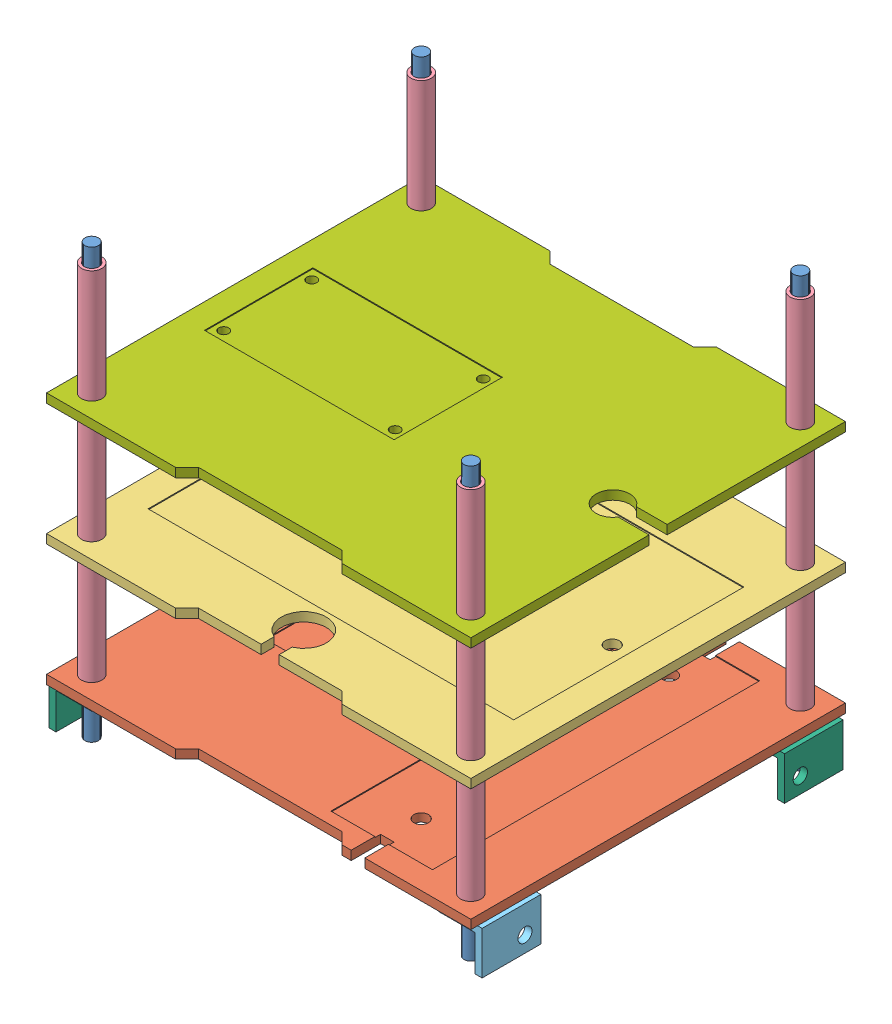
SolidWorks assembly PCB_Stack_3, configuration Default. Lengths in mm.
Overall size (96 95 83).
23 component instances, 7 part files, 68 mates.
Components (placement in the parent):
- PCB_Rod_2-1: PCB_Rod_2 [Default] at origin size (3 95 3)
- PCB_Rod_2-2: PCB_Rod_2 [Default] at (-84 0 0.0003) x (-0.139284 0 0.990253) z (-0.990253 0 -0.139284) size (3 95 3)
- PCB_Rod_2-3: PCB_Rod_2 [Default] at (-83.9998 0 73.0003) x (0.037489 0 0.999297) z (-0.999297 0 0.037489) size (3 95 3)
- PCB_Rod_2-4: PCB_Rod_2 [Default] at (0.0002 0 73) x (0.981991 0 -0.188925) z (0.188925 0 0.981991) size (3 95 3)
- PCB_Battery-1: PCB_Battery [Default] at (-41.9999 10 36.5001) x (-1 0 0.000003) z (-0.000003 0 -1) size (94 2 83)
- PCB-2: PCB [Default] at (-41.9999 37 36.5001) x (1 0 -0.000003) z (0.000003 0 1) size (94 2 83)
- Aluminum Unthreaded Spacer_Battery-1: Aluminum Unthreaded Spacer_Battery [94669A105] at (0 24.5 0) x (0.317635 0 -0.948213) z (0 1 0) size (4.5 4.5 25)
- Aluminum Unthreaded Spacer_Battery-2: Aluminum Unthreaded Spacer_Battery [94669A105] at (0 51.5 0) x (0.317635 0 -0.948213) z (0 1 0) size (4.5 4.5 25)
- Aluminum Unthreaded Spacer_Battery-3: Aluminum Unthreaded Spacer_Battery [94669A105] at (0 78.5 0) x (-0.841831 0 -0.539741) z (0 1 0) size (4.5 4.5 25)
- Aluminum Unthreaded Spacer_Battery-4: Aluminum Unthreaded Spacer_Battery [94669A105] at (0.0002 24.5 73) x (0.317635 0 -0.948213) z (0 1 0) size (4.5 4.5 25)
- Aluminum Unthreaded Spacer_Battery-5: Aluminum Unthreaded Spacer_Battery [94669A105] at (0.0002 51.5 73) x (0.317635 0 -0.948213) z (0 1 0) size (4.5 4.5 25)
- Aluminum Unthreaded Spacer_Battery-6: Aluminum Unthreaded Spacer_Battery [94669A105] at (0.0002 78.5 73) x (-0.286549 0 -0.958066) z (0 1 0) size (4.5 4.5 25)
- Aluminum Unthreaded Spacer_Battery-7: Aluminum Unthreaded Spacer_Battery [94669A105] at (-83.9998 24.5 73.0003) x (0.317635 0 -0.948213) z (0 1 0) size (4.5 4.5 25)
- Aluminum Unthreaded Spacer_Battery-8: Aluminum Unthreaded Spacer_Battery [94669A105] at (-83.9998 51.5 73.0003) x (0.317635 0 -0.948213) z (0 1 0) size (4.5 4.5 25)
- Aluminum Unthreaded Spacer_Battery-9: Aluminum Unthreaded Spacer_Battery [94669A105] at (-83.9998 78.5 73.0003) x (-0.883236 0 -0.468929) z (0 1 0) size (4.5 4.5 25)
- Aluminum Unthreaded Spacer_Battery-10: Aluminum Unthreaded Spacer_Battery [94669A105] at (-84 51.5 0.0003) x (0.317635 0 -0.948213) z (0 1 0) size (4.5 4.5 25)
- Aluminum Unthreaded Spacer_Battery-11: Aluminum Unthreaded Spacer_Battery [94669A105] at (-84 78.5 0.0003) x (-0.872408 0 -0.488777) z (0 1 0) size (4.5 4.5 25)
- Aluminum Unthreaded Spacer_Battery-12: Aluminum Unthreaded Spacer_Battery [94669A105] at (-84 24.5 0.0003) x (0.317635 0 -0.948213) z (0 1 0) size (4.5 4.5 25)
- 88805K144_Architectural 6063 Aluminum 90 Degree Angle-1: 88805K144_Architectural 6063 Aluminum 90 Degree Angle [88805K144] at (-85.2375 5.2375 3.0003) x (-1 0 0.000003) z (0.000003 0 1) size (9.53 9.53 13)
- 88805K144_Architectural 6063 Aluminum 90 Degree Angle-2: 88805K144_Architectural 6063 Aluminum 90 Degree Angle [88805K144] at (1.2377 5.2375 70) x (0 1 0) z (0.000003 0 1) size (9.53 9.53 13)
- PCB_Bracket_1_(88805K144_Architectural 6063 Aluminum 90 Degree Angle)-1: PCB_Bracket_1_(88805K144_Architectural 6063 Aluminum 90 Degree Angle) [88805K144] at (1.2375 5.2375 3) x (0 1 0) z (0.000003 0 1) size (9.53 9.53 13)
- PCB_Bracket_1_(88805K144_Architectural 6063 Aluminum 90 Degree Angle)-2: PCB_Bracket_1_(88805K144_Architectural 6063 Aluminum 90 Degree Angle) [88805K144] at (-85.2373 5.2375 70.0003) x (0 1 0) z (-0.000003 0 -1) size (9.53 9.53 13)
- PCB2-1: PCB2 [Default] at (-41.9999 64 36.5001) x (1 0 -0.000003) z (0.000003 0 1) size (94 2 83)
Mates (geometry in assembly coordinates):
- Concentric1: concentric aligned: cylinder of PCB_Rod_2-1 through (0 95 0) axis (0 -1 0) radius 1.5; cylinder of PCB_Battery-1 through (0 12 0) axis (0 -1 0) radius 1.5875
- Concentric2: concentric aligned: cylinder of PCB_Rod_2-4 through (0.0002 95 73) axis (0 -1 0) radius 1.5; cylinder of PCB_Battery-1 through (0.0002 12 73) axis (0 -1 0) radius 1.5875
- Concentric3: concentric aligned: cylinder of PCB_Rod_2-3 through (-83.9998 95 73.0003) axis (0 -1 0) radius 1.5; cylinder of PCB_Battery-1 through (-83.9998 12 73.0003) axis (0 -1 0) radius 1.5875
- Concentric4: concentric aligned: cylinder of PCB_Rod_2-2 through (-84 95 0.0003) axis (0 -1 0) radius 1.5; cylinder of PCB_Battery-1 through (-84 12 0.0003) axis (0 -1 0) radius 1.5875
- Concentric10: concentric aligned: cylinder of PCB_Rod_2-2 through (-84 95 0.0003) axis (0 -1 0) radius 1.5; cylinder of PCB-2 through (-84 39 0.0003) axis (0 -1 0) radius 1.5875
- Concentric11: concentric aligned: cylinder of PCB_Rod_2-3 through (-83.9998 95 73.0003) axis (0 -1 0) radius 1.5; cylinder of PCB-2 through (-83.9998 39 73.0003) axis (0 -1 0) radius 1.5875
- Concentric12: concentric aligned: cylinder of PCB_Rod_2-1 through (0 95 0) axis (0 -1 0) radius 1.5; cylinder of PCB-2 through (0 39 0) axis (0 -1 0) radius 1.5875
- Concentric13: concentric aligned: cylinder of PCB_Rod_2-4 through (0.0002 95 73) axis (0 -1 0) radius 1.5; cylinder of PCB-2 through (0.0002 39 73) axis (0 -1 0) radius 1.5875
- Distance1: distance = 25 mm anti-aligned: plane of PCB-2 through (-41.9999 37 36.5001) normal (0 -1 0); plane of PCB_Battery-1 through (-41.9999 12 36.5001) normal (0 1 0)
- Concentric14: concentric aligned: cylinder of PCB_Rod_2-4 through (0.0002 95 73) axis (0 -1 0) radius 1.5; cylinder of PCB-1 through (0.0002 66 73) axis (0 -1 0) radius 1.5
- Concentric15: concentric aligned: cylinder of PCB_Rod_2-1 through (0 95 0) axis (0 -1 0) radius 1.5; cylinder of PCB-1 through (0 66 0) axis (0 -1 0) radius 1.5
- Distance2: distance = 25 mm anti-aligned: plane of PCB-1 through (-41.9999 64 36.5001) normal (0 -1 0); plane of PCB-2 through (-41.9999 39 36.5001) normal (0 1 0)
- Concentric16: concentric anti-aligned: cylinder of PCB_Rod_2-1 through (0 95 0) axis (0 -1 0) radius 1.5; cylinder of Mounting_Standoff-1 through (0 4 0) axis (0 1 0) radius 1.55
- Coincident1: coincident anti-aligned: plane of Mounting_Standoff-1 through (-41.9999 10 36.5001) normal (0 1 0); plane of PCB_Battery-1 through (-41.9999 10 36.5001) normal (0 -1 0)
- Parallel1: parallel aligned: plane of Mounting_Standoff-1 through (6 4 -7.5) normal (1 0 -0.000003); plane of PCB_Battery-1 through (5 12 -5) normal (1 0 -0.000003)
- Concentric17: concentric aligned: cylinder of PCB_Rod_2-2 through (-84 95 0.0003) axis (0 -1 0) radius 1.5; cylinder of Mounting_Standoff-2 through (-84 10 0.0003) axis (0 -1 0) radius 1.55
- Parallel3: parallel aligned: plane of PCB_Battery-1 through (-89 12 -4.9997) normal (-1 0 0.000003); plane of Mounting_Standoff-2 through (-90 10 -7.4997) normal (-1 0 0.000003)
- Coincident2: coincident anti-aligned: plane of PCB_Battery-1 through (-41.9999 10 36.5001) normal (0 -1 0); plane of Mounting_Standoff-2 through (-41.9999 10 36.5001) normal (0 1 0)
- Concentric18: concentric aligned: cylinder of PCB_Rod_2-4 through (0.0002 95 73) axis (0 -1 0) radius 1.5; cylinder of Mounting_Standoff-3 through (0.0002 10 73) axis (0 -1 0) radius 1.55
- Coincident3: coincident anti-aligned: plane of PCB_Battery-1 through (-41.9999 10 36.5001) normal (0 -1 0); plane of Mounting_Standoff-3 through (-41.9999 10 36.5001) normal (0 1 0)
- Parallel4: parallel aligned: plane of PCB_Battery-1 through (5.0003 12 78) normal (0.000003 0 1); plane of Mounting_Standoff-3 through (0.5003 10 80.5) normal (0.000003 0 1)
- Concentric19: concentric anti-aligned: cylinder of PCB_Rod_2-3 through (-83.9998 95 73.0003) axis (0 -1 0) radius 1.5; cylinder of Mounting_Standoff-4 through (-83.9998 4 73.0003) axis (0 1 0) radius 1.55
- Coincident5: coincident anti-aligned: plane of PCB_Battery-1 through (-41.9999 10 36.5001) normal (0 -1 0); plane of Mounting_Standoff-4 through (-41.9999 10 36.5001) normal (0 1 0)
- Parallel5: parallel aligned: plane of PCB_Battery-1 through (5.0003 12 78) normal (0.000003 0 1); plane of Mounting_Standoff-4 through (-84.4997 4 80.5003) normal (0.000003 0 1)
- Distance3: distance = 10 mm aligned: plane of PCB_Battery-1 through (-41.9999 10 36.5001) normal (0 -1 0); plane of PCB_Rod_2-1 through (0 0 0) normal (0 -1 0)
- Coincident6: coincident aligned: plane of PCB_Rod_2-1 through (0 0 0) normal (0 -1 0); plane of PCB_Rod_2-4 through (0.0002 0 73) normal (0 -1 0)
- Coincident7: coincident aligned: plane of PCB_Rod_2-1 through (0 0 0) normal (0 -1 0); plane of PCB_Rod_2-2 through (-84 0 0.0003) normal (0 -1 0)
- Coincident8: coincident aligned: plane of PCB_Rod_2-1 through (0 0 0) normal (0 -1 0); plane of PCB_Rod_2-3 through (-83.9998 0 73.0003) normal (0 -1 0)
- Concentric20: concentric aligned: cylinder of PCB_Rod_2-1 through (0 95 0) axis (0 -1 0) radius 1.5; cylinder of Aluminum Unthreaded Spacer_Battery-1 through (0 37 0) axis (0 -1 0) radius 1.6
- Coincident9: coincident anti-aligned: plane of PCB-2 through (-41.9999 37 36.5001) normal (0 -1 0); plane of Aluminum Unthreaded Spacer_Battery-1 through (0 37 0) normal (0 1 0)
- Concentric21: concentric aligned: cylinder of PCB_Rod_2-1 through (0 95 0) axis (0 -1 0) radius 1.5; cylinder of Aluminum Unthreaded Spacer_Battery-2 through (0 64 0) axis (0 -1 0) radius 1.6
- Coincident10: coincident anti-aligned: plane of PCB-1 through (-41.9999 64 36.5001) normal (0 -1 0); plane of Aluminum Unthreaded Spacer_Battery-2 through (0 64 0) normal (0 1 0)
- Concentric22: concentric aligned: cylinder of PCB_Rod_2-1 through (0 95 0) axis (0 -1 0) radius 1.5; cylinder of Aluminum Unthreaded Spacer_Battery-3 through (0 91 0) axis (0 -1 0) radius 1.6
- Coincident11: coincident anti-aligned: plane of PCB-1 through (-41.9999 66 36.5001) normal (0 1 0); plane of Aluminum Unthreaded Spacer_Battery-3 through (0 66 0) normal (0 -1 0)
- Concentric23: concentric aligned: cylinder of PCB_Rod_2-4 through (0.0002 95 73) axis (0 -1 0) radius 1.5; cylinder of Aluminum Unthreaded Spacer_Battery-4 through (0.0002 37 73) axis (0 -1 0) radius 1.6
- Coincident12: coincident anti-aligned: plane of PCB-2 through (-41.9999 37 36.5001) normal (0 -1 0); plane of Aluminum Unthreaded Spacer_Battery-4 through (0.0002 37 73) normal (0 1 0)
- Concentric24: concentric aligned: cylinder of PCB_Rod_2-4 through (0.0002 95 73) axis (0 -1 0) radius 1.5; cylinder of Aluminum Unthreaded Spacer_Battery-5 through (0.0002 64 73) axis (0 -1 0) radius 1.6
- Coincident13: coincident anti-aligned: plane of PCB-1 through (-41.9999 64 36.5001) normal (0 -1 0); plane of Aluminum Unthreaded Spacer_Battery-5 through (0.0002 64 73) normal (0 1 0)
- Concentric25: concentric aligned: cylinder of PCB_Rod_2-4 through (0.0002 95 73) axis (0 -1 0) radius 1.5; cylinder of Aluminum Unthreaded Spacer_Battery-6 through (0.0002 91 73) axis (0 -1 0) radius 1.6
- Coincident14: coincident anti-aligned: plane of PCB-1 through (-41.9999 66 36.5001) normal (0 1 0); plane of Aluminum Unthreaded Spacer_Battery-6 through (0.0002 66 73) normal (0 -1 0)
- Concentric26: concentric aligned: cylinder of PCB_Rod_2-3 through (-83.9998 95 73.0003) axis (0 -1 0) radius 1.5; cylinder of Aluminum Unthreaded Spacer_Battery-7 through (-83.9998 37 73.0003) axis (0 -1 0) radius 1.6
- Coincident15: coincident anti-aligned: plane of PCB-2 through (-41.9999 37 36.5001) normal (0 -1 0); plane of Aluminum Unthreaded Spacer_Battery-7 through (-83.9998 37 73.0003) normal (0 1 0)
- Concentric27: concentric aligned: cylinder of PCB_Rod_2-3 through (-83.9998 95 73.0003) axis (0 -1 0) radius 1.5; cylinder of Aluminum Unthreaded Spacer_Battery-8 through (-83.9998 64 73.0003) axis (0 -1 0) radius 1.6
- Coincident16: coincident anti-aligned: plane of PCB-1 through (-41.9999 64 36.5001) normal (0 -1 0); plane of Aluminum Unthreaded Spacer_Battery-8 through (-83.9998 64 73.0003) normal (0 1 0)
- Concentric28: concentric aligned: cylinder of PCB_Rod_2-3 through (-83.9998 95 73.0003) axis (0 -1 0) radius 1.5; cylinder of Aluminum Unthreaded Spacer_Battery-9 through (-83.9998 91 73.0003) axis (0 -1 0) radius 1.6
- Coincident17: coincident anti-aligned: plane of PCB-1 through (-41.9999 66 36.5001) normal (0 1 0); plane of Aluminum Unthreaded Spacer_Battery-9 through (-83.9998 66 73.0003) normal (0 -1 0)
- Concentric29: concentric aligned: cylinder of PCB_Rod_2-2 through (-84 95 0.0003) axis (0 -1 0) radius 1.5; cylinder of Aluminum Unthreaded Spacer_Battery-12 through (-84 37 0.0003) axis (0 -1 0) radius 1.6
- Coincident18: coincident anti-aligned: plane of PCB-2 through (-41.9999 37 36.5001) normal (0 -1 0); plane of Aluminum Unthreaded Spacer_Battery-12 through (-84 37 0.0003) normal (0 1 0)
- Concentric30: concentric aligned: cylinder of PCB_Rod_2-2 through (-84 95 0.0003) axis (0 -1 0) radius 1.5; cylinder of Aluminum Unthreaded Spacer_Battery-10 through (-84 64 0.0003) axis (0 -1 0) radius 1.6
- Coincident19: coincident anti-aligned: plane of PCB-1 through (-41.9999 64 36.5001) normal (0 -1 0); plane of Aluminum Unthreaded Spacer_Battery-10 through (-84 64 0.0003) normal (0 1 0)
- Concentric31: concentric aligned: cylinder of PCB_Rod_2-2 through (-84 95 0.0003) axis (0 -1 0) radius 1.5; cylinder of Aluminum Unthreaded Spacer_Battery-11 through (-84 91 0.0003) axis (0 -1 0) radius 1.6
- Coincident20: coincident anti-aligned: plane of PCB-1 through (-41.9999 66 36.5001) normal (0 1 0); plane of Aluminum Unthreaded Spacer_Battery-11 through (-84 66 0.0003) normal (0 -1 0)
- Concentric33: concentric anti-aligned: circle of PCB_Rod_2-2; circle of 88805K144_Architectural 6063 Aluminum 90 Degree Angle-1
- Coincident22: coincident anti-aligned: plane of PCB_Battery-1 through (-41.9999 10 36.5001) normal (0 -1 0); plane of 88805K144_Architectural 6063 Aluminum 90 Degree Angle-1 through (-80.475 10 9.5003) normal (0 1 0)
- Parallel6: parallel anti-aligned: line of PCB_Battery-1 through (-89 10 -4.9997) axis (0.000003 0 1); line of 88805K144_Architectural 6063 Aluminum 90 Degree Angle-1 through (-90 10 9.5003) axis (-0.000003 0 -1)
- Concentric34: concentric anti-aligned: cylinder of PCB_Rod_2-4 through (0.0002 95 73) axis (0 -1 0) radius 1.5; circle of 88805K144_Architectural 6063 Aluminum 90 Degree Angle-2
- Coincident24: coincident anti-aligned: plane of PCB_Battery-1 through (-41.9999 10 36.5001) normal (0 -1 0); plane of 88805K144_Architectural 6063 Aluminum 90 Degree Angle-2 through (6.0002 10 76.5) normal (0 1 0)
- Parallel7: parallel aligned: line of PCB_Battery-1 through (5.0003 10 78) axis (-0.000003 0 -1); line of 88805K144_Architectural 6063 Aluminum 90 Degree Angle-2 through (6.0002 10 76.5) axis (-0.000003 0 -1)
- Concentric35: concentric anti-aligned: cylinder of PCB_Rod_2-1 through (0 95 0) axis (0 -1 0) radius 1.5; circle of PCB_Bracket_1_(88805K144_Architectural 6063 Aluminum 90 Degree Angle)-1
- Coincident26: coincident anti-aligned: plane of PCB_Battery-1 through (-41.9999 10 36.5001) normal (0 -1 0); plane of PCB_Bracket_1_(88805K144_Architectural 6063 Aluminum 90 Degree Angle)-1 through (6 10 9.5) normal (0 1 0)
- Parallel8: parallel aligned: line of PCB_Battery-1 through (5.0003 10 78) axis (-0.000003 0 -1); line of PCB_Bracket_1_(88805K144_Architectural 6063 Aluminum 90 Degree Angle)-1 through (6 10 9.5) axis (-0.000003 0 -1)
- Concentric36: concentric anti-aligned: cylinder of PCB_Rod_2-3 through (-83.9998 95 73.0003) axis (0 -1 0) radius 1.5; cylinder of PCB_Bracket_1_(88805K144_Architectural 6063 Aluminum 90 Degree Angle)-2 through (-83.9998 0 73.0003) axis (0 1 0) radius 1.5875
- Coincident28: coincident anti-aligned: plane of PCB_Battery-1 through (-41.9999 10 36.5001) normal (0 -1 0); plane of PCB_Bracket_1_(88805K144_Architectural 6063 Aluminum 90 Degree Angle)-2 through (-89.9998 10 63.5003) normal (0 1 0)
- Parallel9: parallel aligned: line of PCB_Battery-1 through (-89 10 -4.9997) axis (0.000003 0 1); line of PCB_Bracket_1_(88805K144_Architectural 6063 Aluminum 90 Degree Angle)-2 through (-89.9998 10 63.5003) axis (0.000003 0 1)
- Concentric37: concentric aligned: cylinder of PCB_Rod_2-3 through (-83.9998 95 73.0003) axis (0 -1 0) radius 1.5; cylinder of PCB2-1 through (-83.9998 66 73.0003) axis (0 -1 0) radius 1.5875
- Parallel10: parallel aligned: line of PCB-2 through (5 39 -5) axis (-1 0 0.000003); line of PCB2-1 through (5 66 -5) axis (-1 0 0.000003)
- Coincident30: coincident anti-aligned: plane of Aluminum Unthreaded Spacer_Battery-10 through (-84 64 0.0003) normal (0 1 0); plane of PCB2-1 through (-41.9999 64 36.5001) normal (0 -1 0)
- Coincident31: coincident anti-aligned: plane of PCB-2 through (-41.9999 39 36.5001) normal (0 1 0); plane of Aluminum Unthreaded Spacer_Battery-10 through (-84 39 0.0003) normal (0 -1 0)
